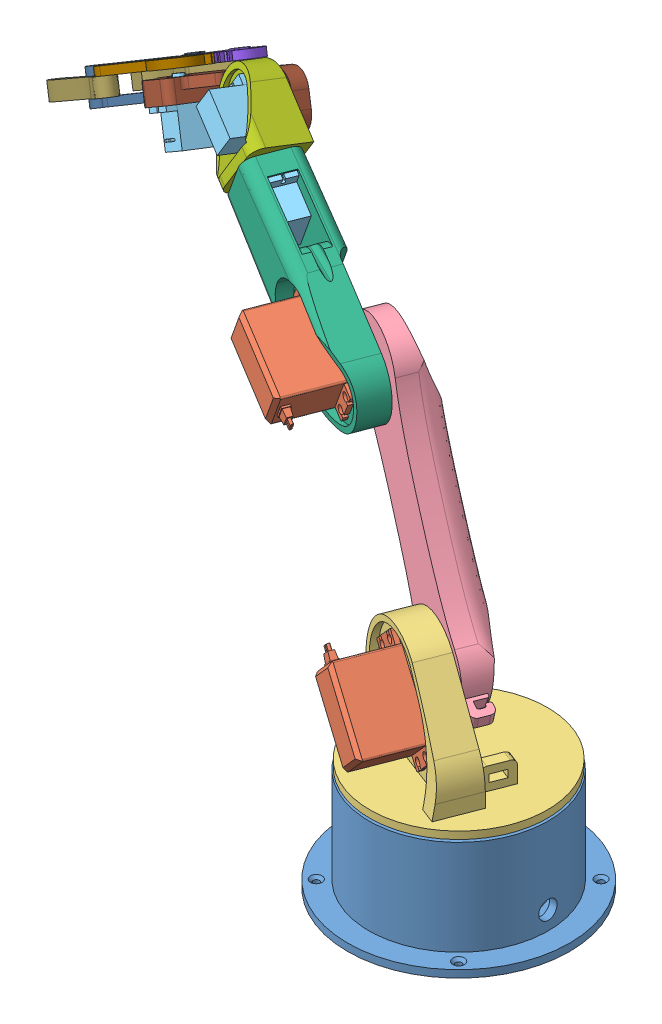
SolidWorks assembly Robotic Arm, configuration Default. Lengths in mm.
Overall size (363.37 287 194.64).
21 component instances, 12 part files, 26 mates.
Components (placement in the parent):
- Base-1: Base [Default] at (40.7793 36.1076 92.8796) size (121.25 56 121.25)
- Servo Motor MG996R-1: Servo Motor MG996R [Default] at (30.5293 45.3076 92.8796) x (-1 0 0) z (0 0 -1) size (55.8 47.4 21)
- Waist-1: Waist [Default] at (40.7793 93.1076 92.8796) x (0.361416 0 -0.932405) z (0.932405 0 0.361416) size (97 64.78 97)
- Servo Motor MG996R-2: Servo Motor MG996R [Default] at (16.9426 126.313 136.4069) x (0.65931 -0.707107 0.25556) z (0.65931 0.707107 0.25556) size (55.8 47.4 21)
- Arm 01-1: Arm 01 [Default] at (27.3159 133.5608 89.5914) x (-0.792522 -0.52682 -0.307196) z (0.361416 0 -0.932405) size (54.87 166.68 26.36)
- Servo Motor Micro  9g-1: Servo Motor Micro  9g [Default] at (-86.6943 263.6977 56.8748) x (0.424572 0.890312 0.164571) z (-0.361416 0 0.932405) size (32.6 29.9 12.4)
- Servo Motor MG996R-7: Servo Motor MG996R [Default] at (-57.2693 240.2254 107.641) x (-0.830131 0.455351 -0.321773) z (-0.424572 -0.890312 -0.164571) size (55.8 47.4 21)
- Arm 02 v3-1: Arm 02 v3 [Default] at (-62.2495 251.6041 60.4513) x (0.424572 0.890312 0.164571) z (-0.361416 0 0.932405) size (38.57 115 28.32)
- Arm 03-1: Arm 03 [Default] at (-111.1835 277.0914 46.0848) x (0.499405 0.863857 -0.065926) z (-0.247947 0.215422 0.944519) size (33 46 28)
- Servo Motor Micro  9g-2: Servo Motor Micro  9g [Default] at (-133.8011 290.6534 52.459) x (0.830131 -0.455351 0.321773) z (0.499405 0.863857 -0.065926) size (32.6 29.9 12.4)
- Gripper Assembly-1: Gripper Assembly [Default] at (-120.5709 301.3075 30.3443) x (-0.247947 0.215422 0.944519) z (-0.842754 -0.528811 -0.100623) size (98.22 36.05 139.41)
  - gear1-1: gear1 [Default] at (-22.9056 12.6028 63.2843) x (-0.581668 0 0.813426) z (-0.813426 0 -0.581668) size (49.29 4 26.63)
  - gear2-1: gear2 [Default] at (5.149 12.6028 46.1292) x (-0.467421 0 -0.884035) z (0.884035 0 -0.467421) size (49.02 4 26.63)
  - grip link 1-1: grip link 1 [Default] at (-26.7426 0.1028 100.5029) x (0.571471 0 -0.820623) z (0.820623 0 0.571471) size (39 4 8)
  - Gripper base-1: Gripper base [Default] at (-22.027 4.1028 80.0636) size (44.4 28 77)
  - grip link 1-2: grip link 1 [Default] at (18.9346 0.1028 100.3298) x (-0.579406 0 -0.815039) z (0.815039 0 -0.579406) size (39 4 8)
  - Gripper 1-1: Gripper 1 [Default] at (25.0683 4.1028 73.5645) x (0 1 0) z (0.39713 0 -0.917762) size (8.5 22.22 65.31)
  - Gripper 1-2: Gripper 1 [Default] at (-32.1279 12.6028 73.5771) x (0 -1 0) z (-0.371396 0 -0.928475) size (8.5 22.22 65.31)
  - Servo Motor Micro  9g-1: Servo Motor Micro  9g [Default] at (4.773 -19.4472 55.0636) x (-1 0 0) z (0 0 -1) size (32.6 29.9 12.4)
  - grip link 1-3: grip link 1 [Default] at (18.9346 12.6028 100.3298) x (-0.579406 0 -0.815039) z (0.815039 0 -0.579406) size (39 4 8)
  - grip link 1-4: grip link 1 [Default] at (-26.7426 16.6028 100.5029) x (0.571471 0 -0.820623) z (-0.820623 0 -0.571471) size (39 4 8)
Mates (geometry in assembly coordinates):
- Coincident1: coincident anti-aligned: plane of Base-1 through (40.7793 74.1076 105.8796) normal (0 1 0); plane of Servo Motor MG996R-1 through (57.8293 74.1076 102.1296) normal (0 -1 0)
- Concentric1: concentric aligned: cylinder of Base-1 through (54.5293 66.9076 87.8796) axis (0 1 0) radius 1.3; cylinder of Servo Motor MG996R-1 through (54.5293 69.7076 87.8796) axis (0 1 0) radius 2.1
- Concentric4: concentric aligned: cylinder of Base-1 through (6.5293 66.9076 97.8796) axis (0 1 0) radius 1.3; cylinder of Servo Motor MG996R-1 through (6.5293 69.7076 97.8796) axis (0 1 0) radius 2.1
- Concentric5: concentric aligned: cylinder of Base-1 through (40.7793 92.1076 92.8796) axis (0 -1 0) radius 49; cylinder of Waist-1 through (40.7793 97.1076 92.8796) axis (0 -1 0) radius 48.5
- Distance1: distance = 1 mm anti-aligned: plane of Base-1 through (40.7793 92.1076 92.8796) normal (0 1 0); plane of Waist-1 through (40.7793 93.1076 92.8796) normal (0 -1 0)
- Coincident4: coincident anti-aligned: plane of Waist-1 through (34.2738 93.1076 109.6628) normal (-0.361416 0 0.932405); plane of Servo Motor MG996R-2 through (4.1211 139.0763 97.9751) normal (0.361416 0 -0.932405)
- Coincident5: coincident anti-aligned: plane of Waist-1 through (37.469 119.0651 143.6136) normal (-0.65931 0.707107 -0.25556); plane of Servo Motor MG996R-2 through (50.5888 119.0651 109.7664) normal (0.65931 -0.707107 0.25556)
- Coincident6: coincident anti-aligned: plane of Waist-1 through (37.469 119.0651 143.6136) normal (-0.65931 -0.707107 -0.25556); plane of Servo Motor MG996R-2 through (23.5571 148.0565 99.2884) normal (0.65931 0.707107 0.25556)
- Coincident7: coincident anti-aligned: plane of Servo Motor MG996R-2 through (27.3159 133.5608 89.5914) normal (0.361416 0 -0.932405); plane of Arm 01-1 through (27.3159 133.5608 89.5914) normal (-0.361416 0 0.932405)
- Concentric8: concentric aligned: cylinder of Servo Motor MG996R-2 through (27.3159 133.5608 89.5914) axis (-0.361416 0 0.932405) radius 10.5; cylinder of Arm 01-1 through (29.1229 133.5608 84.9294) axis (-0.361416 0 0.932405) radius 21
- Coincident25: coincident anti-aligned: plane of Servo Motor MG996R-7 through (-64.7283 260.8919 71.2879) normal (0.361416 0 -0.932405); plane of Arm 02 v3-1 through (-66.2251 251.6041 70.7077) normal (-0.361416 0 0.932405)
- Coincident26: coincident anti-aligned: plane of Servo Motor MG996R-7 through (-31.231 221.765 78.0516) normal (-0.424572 -0.890312 -0.164571); plane of Arm 02 v3-1 through (-33.3272 221.765 83.4595) normal (0.424572 0.890312 0.164571)
- Coincident27: coincident anti-aligned: plane of Servo Motor MG996R-7 through (-65.2664 240.4344 64.8589) normal (-0.830131 0.455351 -0.321773); plane of Arm 02 v3-1 through (-67.3626 240.4344 70.2668) normal (0.830131 -0.455351 0.321773)
- Concentric13: concentric anti-aligned: cylinder of Arm 01-1 through (-31.6296 235.5581 66.7442) axis (0.361416 0 -0.932405) radius 3.75; cylinder of Servo Motor MG996R-7 through (-31.6293 235.5581 66.7432) axis (-0.361416 0 0.932405) radius 10.5
- Coincident28: coincident anti-aligned: plane of Arm 01-1 through (27.3159 133.5608 89.5914) normal (-0.361416 0 0.932405); plane of Servo Motor MG996R-7 through (-31.6293 235.5581 66.7432) normal (0.361416 0 -0.932405)
- Concentric14: concentric anti-aligned: cylinder of Servo Motor Micro  9g-1 through (-113.6805 272.7722 46.4145) axis (0.830131 -0.455351 0.321773) radius 2.5; cylinder of Arm 02 v3-1 through (-110.4845 271.0191 47.6533) axis (-0.830131 0.455351 -0.321773) radius 6.5
- Coincident30: coincident anti-aligned: plane of Servo Motor Micro  9g-1 through (-96.9984 286.4289 59.5302) normal (-0.830131 0.455351 -0.321773); plane of Arm 02 v3-1 through (-112.0093 255.179 54.0335) normal (0.830131 -0.455351 0.321773)
- Parallel3: parallel anti-aligned: plane of Servo Motor Micro  9g-1 through (-107.7631 263.7916 42.0587) normal (0.361416 0 -0.932405); plane of Arm 02 v3-1 through (-107.3109 255.179 41.9122) normal (-0.361416 0 0.932405)
- Concentric15: concentric aligned: cylinder of Servo Motor Micro  9g-1 through (-113.6805 272.7722 46.4145) axis (0.830131 -0.455351 0.321773) radius 2.5; cylinder of Arm 03-1 through (-123.7011 278.2687 42.5303) axis (0.830131 -0.455351 0.321773) radius 2.5
- Coincident31: coincident anti-aligned: plane of Servo Motor Micro  9g-1 through (-113.6805 272.7722 46.4145) normal (-0.830131 0.455351 -0.321773); plane of Arm 03-1 through (-111.1835 277.0914 46.0848) normal (0.830131 -0.455351 0.321773)
- Concentric16: concentric aligned: cylinder of Arm 03-1 through (-130.9559 286.8254 23.8519) axis (-0.247947 0.215422 0.944519) radius 6.5; cylinder of Servo Motor Micro  9g-2 through (-130.6212 286.5345 22.5768) axis (-0.247947 0.215422 0.944519) radius 2.5
- Parallel6: parallel anti-aligned: plane of Arm 03-1 through (-120.8768 274.0201 31.0065) normal (0.499405 0.863857 -0.065926); plane of Servo Motor Micro  9g-2 through (-140.7487 285.639 28.1689) normal (-0.499405 -0.863857 0.065926)
- Parallel9: parallel anti-aligned: plane of Arm 03-1 through (-139.9698 284.4932 23.6057) normal (0.830131 -0.455351 0.321773); plane of Servo Motor Micro  9g-2 through (-134.5561 296.3508 27.3514) normal (-0.830131 0.455351 -0.321773)
- Coincident46: coincident anti-aligned: plane of Arm 03-1 through (-118.5558 262.0838 43.8668) normal (-0.247947 0.215422 0.944519); plane of Servo Motor Micro  9g-2 through (-139.7605 299.5431 29.7568) normal (0.247947 -0.215422 -0.944519)
- Concentric19: concentric aligned: cylinder of Servo Motor Micro  9g-2 through (-130.6212 286.5345 22.5768) axis (-0.247947 0.215422 0.944519) radius 2.5; cylinder of Gripper Assembly-1/Gripper base-1 through (-127.1499 283.5186 9.3535) axis (-0.247947 0.215422 0.944519) radius 2.5
- Coincident48: coincident anti-aligned: plane of Servo Motor Micro  9g-2 through (-130.6212 286.5345 22.5768) normal (0.247947 -0.215422 -0.944519); plane of Gripper Assembly-1/Gripper base-1 through (-156.6936 285.8651 15.8852) normal (-0.247947 0.215422 0.944519)
